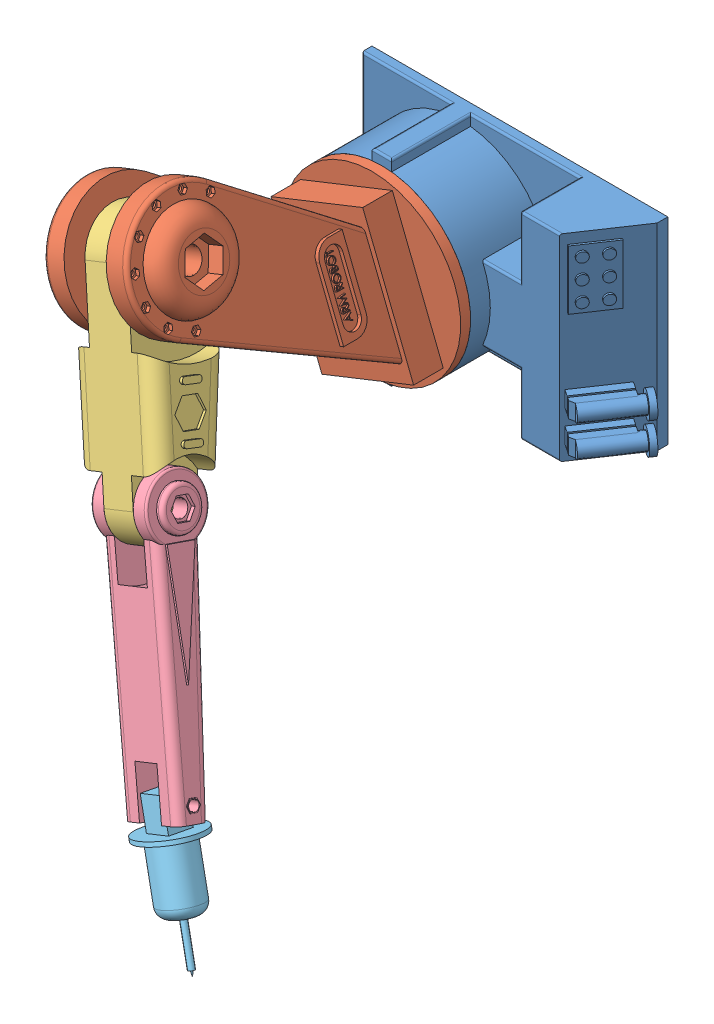
SolidWorks assembly Ass_Bras4DDL, configuration Default. Lengths in mm.
Overall size (182.28 287.41 230.6).
5 component instances, 5 part files, 8 mates.
Components (placement in the parent):
- base_de_robot-1: base_de_robot [Default] at origin size (160.95 100 55)
- link 1-1: link 1 [Default] at (-18.4368 46.4767 145) x (0.368736 -0.929534 0) z (0.929534 0.368736 0) size (125 130 90)
- link 2-1: link 2 [Default] at (12.8151 -32.3052 175.2776) x (0.344423 -0.868243 0.357108) z (0.929534 0.368736 0) size (124.98 40 48)
- link 3-1: link 3 [Default] at (51.0268 -128.6315 205.6932) x (0.353812 -0.89191 0.281626) z (0.929534 0.368736 0) size (130 30 36)
- link 4-1: link 4 [Default] at (73.8273 -186.0235 215.3131) x (0.364342 -0.918457 0.153918) z (0.929534 0.368736 0) size (70 30 30)
Mates (geometry in assembly coordinates):
- Concentric17: concentric: cylinder of base_de_robot-1 through (0 0 55) axis (0 0 -1) radius 10; cylinder of link 1-1 through (0 0 55) axis (0 0 -1) radius 10
- Coincident17: coincident: plane of base_de_robot-1 through (0 0 45) normal (0 0 1); plane of link 1-1 through (0 0 45) normal (0 0 -1)
- Concentric18: concentric: cylinder of link 1-1 through (-20.7607 45.5549 145) axis (-0.929534 -0.368736 0) radius 6; cylinder of link 2-1 through (8.0549 56.9857 145) axis (-0.929534 -0.368736 0) radius 6
- Coincident18: coincident: plane of link 1-1 through (-36.2306 60.1448 92.0938) normal (0.929534 0.368736 0); plane of link 2-1 through (-29.1265 42.2362 145) normal (-0.929534 -0.368736 0)
- Concentric19: concentric: cylinder of link 2-1 through (39.3068 -21.7962 175.2776) axis (-0.929534 -0.368736 0) radius 4; cylinder of link 3-1 through (26.7581 -26.7741 175.2776) axis (-0.929534 -0.368736 0) radius 4
- Coincident21: coincident: plane of link 2-1 through (20.2514 -29.3553 175.2776) normal (0.929534 0.368736 0); plane of link 3-1 through (20.2514 -29.3553 175.2776) normal (-0.929534 -0.368736 0)
- Concentric20: concentric: cylinder of link 3-1 through (67.7584 -121.9942 205.6932) axis (-0.929534 -0.368736 0) radius 2.5; cylinder of link 4-1 through (37.1129 -134.151 205.6932) axis (0.929534 0.368736 0) radius 2.5
- Coincident22: coincident: plane of link 3-1 through (7.2379 -34.5176 175.2776) normal (0.929534 0.368736 0); plane of link 4-1 through (43.4695 -125.8524 210.9291) normal (-0.929534 -0.368736 0)
